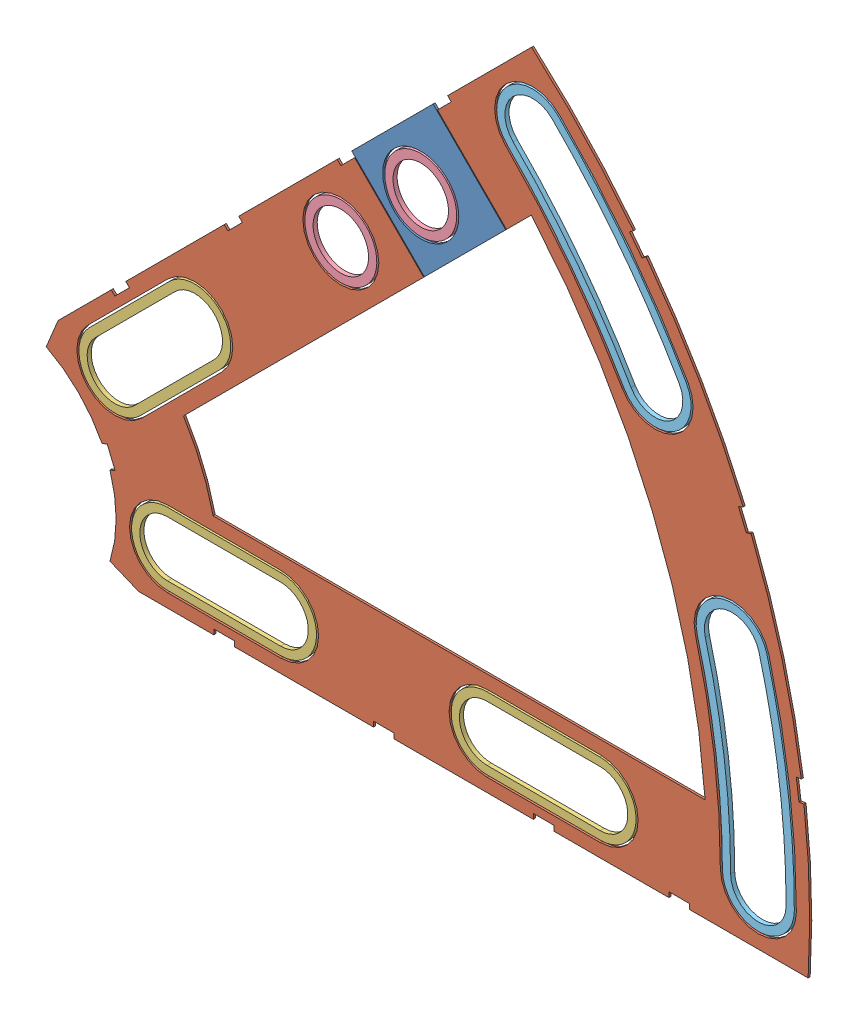
SolidWorks assembly Clover_4_Insul+Pass, configuration Default. Lengths in mm.
Overall size (94.37 82.54 0.51).
9 component instances, 5 part files, 22 mates.
Components (placement in the parent):
- Clover_4_Pass-1: Clover_4_Pass [Default] at (-24.364 -13.218 51.7829) size (19.04 19.04 0.25)
- Clover_4_Insul-1: Clover_4_Insul [Default] at (-24.364 -13.218 51.7829) size (94.37 82.54 0.25)
- Clover_Short_Washer-1: Clover_Short_Washer [Default] at (-3.7094 7.4366 52.0369) x (0.707107 0.707107 0) z (-0.707107 0.707107 0) size (22.86 0.51 8.89)
- Clover_Short_Washer-2: Clover_Short_Washer [Default] at (4.846 -13.218 52.0369) x (1 0 0) z (0 1 0) size (22.86 0.51 8.89)
- Clover_Short_Washer-3: Clover_Short_Washer [Default] at (44.343 -13.218 52.0369) x (1 0 0) z (0 1 0) size (22.86 0.51 8.89)
- Round_Washer-1: Round_Washer [Default] at (19.28 30.4261 52.0369) x (1 0 0) z (0 1 0) size (8.89 0.51 8.89)
- Round_Washer-2: Round_Washer [Default] at (29.1583 40.3043 52.0369) x (1 0 0) z (0 1 0) size (8.89 0.51 8.89)
- Clover_Outside_Washer-1: Clover_Outside_Washer [Default] at (-24.364 -13.218 51.5289) x (0.866025 0.5 0) z (0.5 -0.866025 0) size (12.14 0.51 33.54)
- Clover_Outside_Washer-2: Clover_Outside_Washer [Default] at (-24.364 -13.218 51.5289) x (1 0 0) z (0 -1 0) size (12.14 0.51 33.54)
Mates (geometry in assembly coordinates):
- Coincident1: coincident: plane of Clover_4_Pass-1 through (-24.364 -13.218 52.0369) normal (0 0 1); plane of Clover_4_Insul-1 through (-24.364 -13.218 52.0369) normal (0 0 1)
- Coincident3: coincident: plane of Clover_4_Pass-1 through (42.8474 62.9737 52.0369) normal (-0.707107 0.707107 0); plane of Clover_4_Insul-1 through (42.8474 62.9737 52.0369) normal (-0.707107 0.707107 0)
- Distance1: distance = 2.54 mm: plane of Clover_4_Insul-1 through (18.831 38.9573 51.7829) normal (0.707107 0.707107 0); plane of Clover_4_Pass-1 through (20.6271 40.7534 51.7829) normal (-0.707107 -0.707107 0)
- Concentric1: concentric: circle of Clover_4_Pass-1; circle of Round_Washer-2
- Coincident4: coincident: plane of Clover_4_Pass-1 through (-24.364 -13.218 52.0369) normal (0 0 1); plane of Round_Washer-2 through (29.1583 40.3043 52.0369) normal (0 0 1)
- Concentric2: concentric: circle of Clover_4_Insul-1; circle of Round_Washer-1
- Coincident5: coincident: plane of Clover_4_Insul-1 through (-24.364 -13.218 52.0369) normal (0 0 1); plane of Round_Washer-1 through (19.28 30.4261 52.0369) normal (0 0 1)
- Concentric3: concentric: circle of Clover_4_Insul-1; circle of Clover_Short_Washer-1
- Concentric4: concentric: circle of Clover_4_Insul-1; circle of Clover_Short_Washer-1
- Coincident6: coincident: plane of Clover_4_Insul-1 through (-24.364 -13.218 52.0369) normal (0 0 1); plane of Clover_Short_Washer-1 through (-8.6486 2.4975 52.0369) normal (0 0 1)
- Concentric5: concentric: circle of Clover_4_Insul-1; circle of Clover_Short_Washer-2
- Concentric6: concentric: circle of Clover_4_Insul-1; circle of Clover_Short_Washer-2
- Coincident7: coincident: plane of Clover_4_Insul-1 through (-24.364 -13.218 52.0369) normal (0 0 1); plane of Clover_Short_Washer-2 through (-2.139 -13.218 52.0369) normal (0 0 1)
- Concentric7: concentric: circle of Clover_4_Insul-1; circle of Clover_Short_Washer-3
- Concentric8: concentric: circle of Clover_4_Insul-1; circle of Clover_Short_Washer-3
- Coincident8: coincident: plane of Clover_4_Insul-1 through (-24.364 -13.218 52.0369) normal (0 0 1); plane of Clover_Short_Washer-3 through (37.358 -13.218 52.0369) normal (0 0 1)
- Concentric9: concentric: circle of Clover_4_Insul-1; circle of Clover_Outside_Washer-2
- Concentric10: concentric: circle of Clover_4_Insul-1; circle of Clover_Outside_Washer-2
- Coincident9: coincident: plane of Clover_4_Insul-1 through (-24.364 -13.218 52.0369) normal (0 0 1); plane of Clover_Outside_Washer-2 through (23.261 -13.218 52.0369) normal (0 0 1)
- Concentric11: concentric: circle of Clover_4_Insul-1; circle of Clover_Outside_Washer-1
- Concentric12: concentric: circle of Clover_4_Insul-1; circle of Clover_Outside_Washer-1
- Coincident10: coincident: plane of Clover_4_Insul-1 through (-24.364 -13.218 52.0369) normal (0 0 1); plane of Clover_Outside_Washer-1 through (16.8804 10.5945 52.0369) normal (0 0 1)
